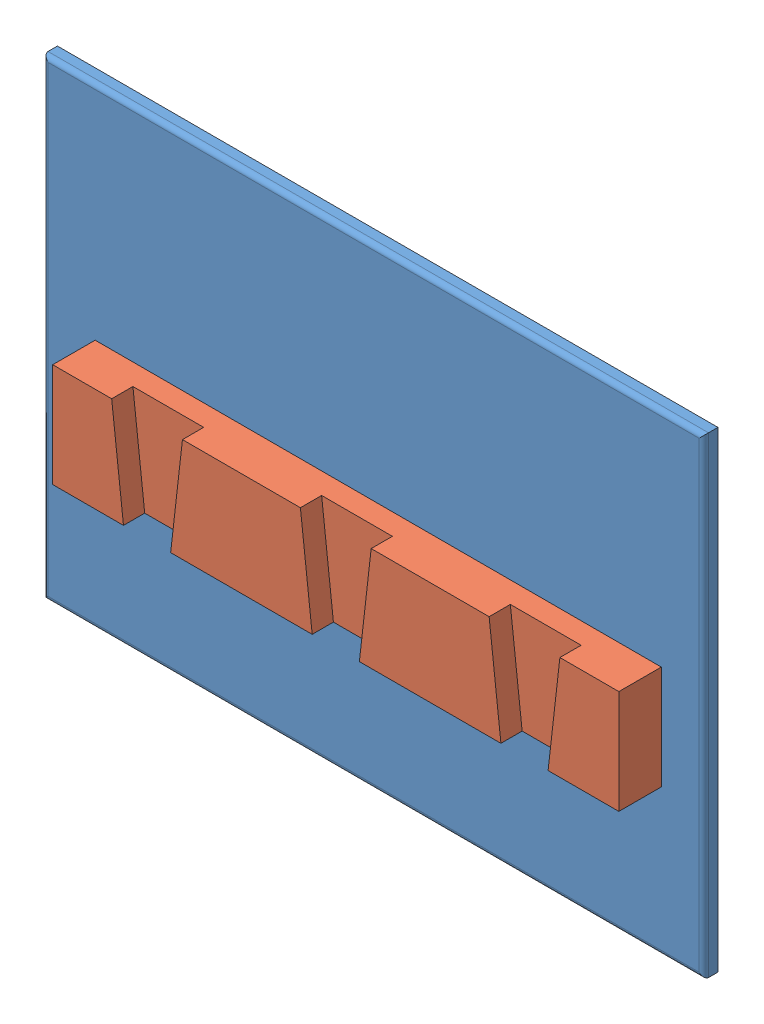
SolidWorks assembly Scissors Assembly, configuration Default. Lengths in mm.
Overall size (280 200 24).
2 component instances, 2 part files, 3 mates.
Components (placement in the parent):
- Backboard-1: Backboard [Default] at (7.7718 -13.8342 5.2977) size (280 200 6)
- Main Body-1: Main Body [Default] at (9.7718 -29.8342 20.2977) size (240 44 18)
Mates (geometry in assembly coordinates):
- Coincident1: coincident: plane of Backboard-1 through (-132.2282 86.1658 11.2977) normal (0 0 1); plane of Main Body-1 through (-110.2282 -7.8342 11.2977) normal (0 0 -1)
- Distance1: distance = 20 mm: line of Backboard-1 through (-130.2282 84.1658 11.2977) axis (0 -1 0); line of Main Body-1 through (-110.2282 -7.8342 11.2977) axis (0 -1 0)
- Distance2: distance = 60 mm: line of Main Body-1 through (-110.2282 -51.8342 11.2977) axis (1 0 0); line of Backboard-1 through (-130.2282 -111.8342 11.2977) axis (1 0 0)
